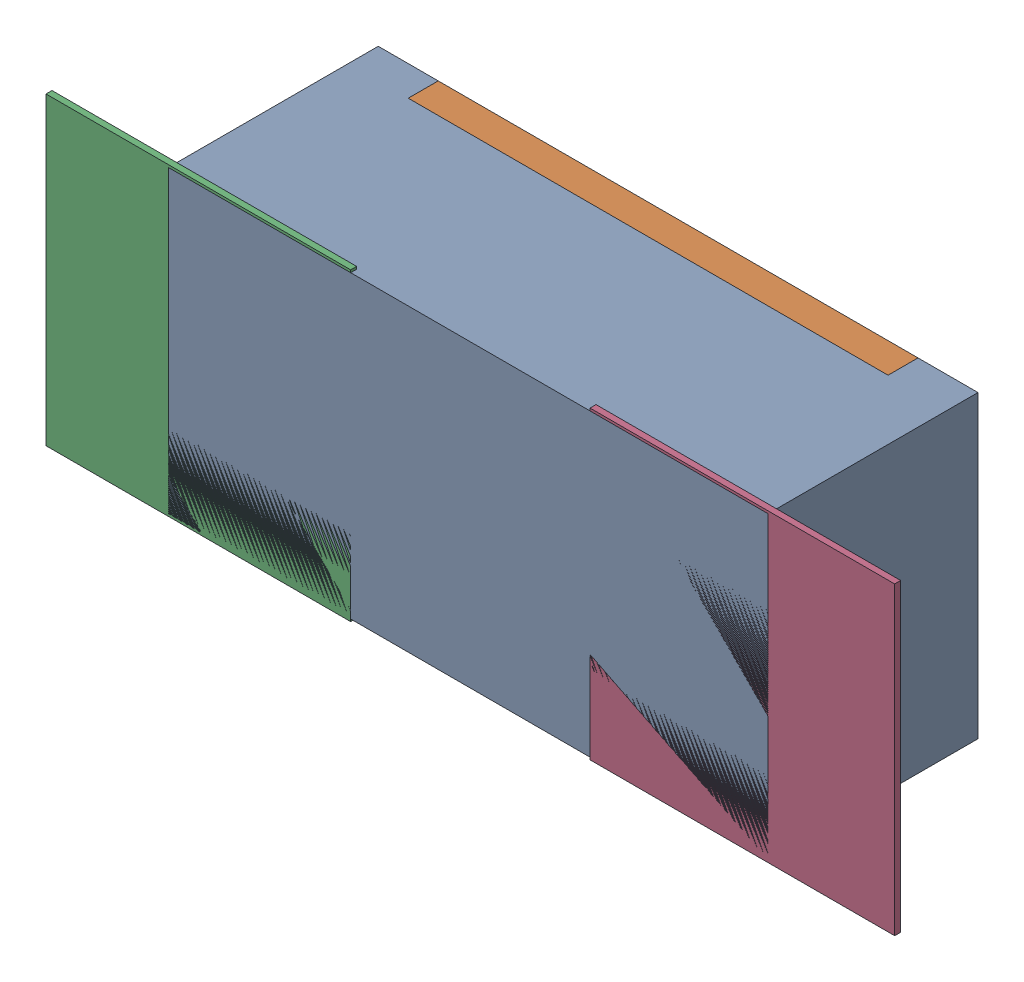
SolidWorks assembly R115, configuration Défaut. Lengths in mm.
Overall size (1.42 0.51 0.35).
5 component instances, 2 part files, 0 mates.
Components (placement in the parent):
- R0402-1: R0402 [Défaut] at (23.2332 -0.6011 -2.0818) x (-1 0 0) z (0 0 -1) size (1 0.5 0.35)
- 6504207776-1: 6504207776 [Défaut] at (22.7832 -0.601 -2.0918) size (0.51 0.51 0.01)
  - Extruded-1: Extruded [Défaut] at origin size (0.51 0.51 0.01)
- 6504207776-2: 6504207776 [Défaut] at (23.6902 -0.601 -2.0918) size (0.51 0.51 0.01)
  - Extruded-1: Extruded [Défaut] at origin size (0.51 0.51 0.01)
